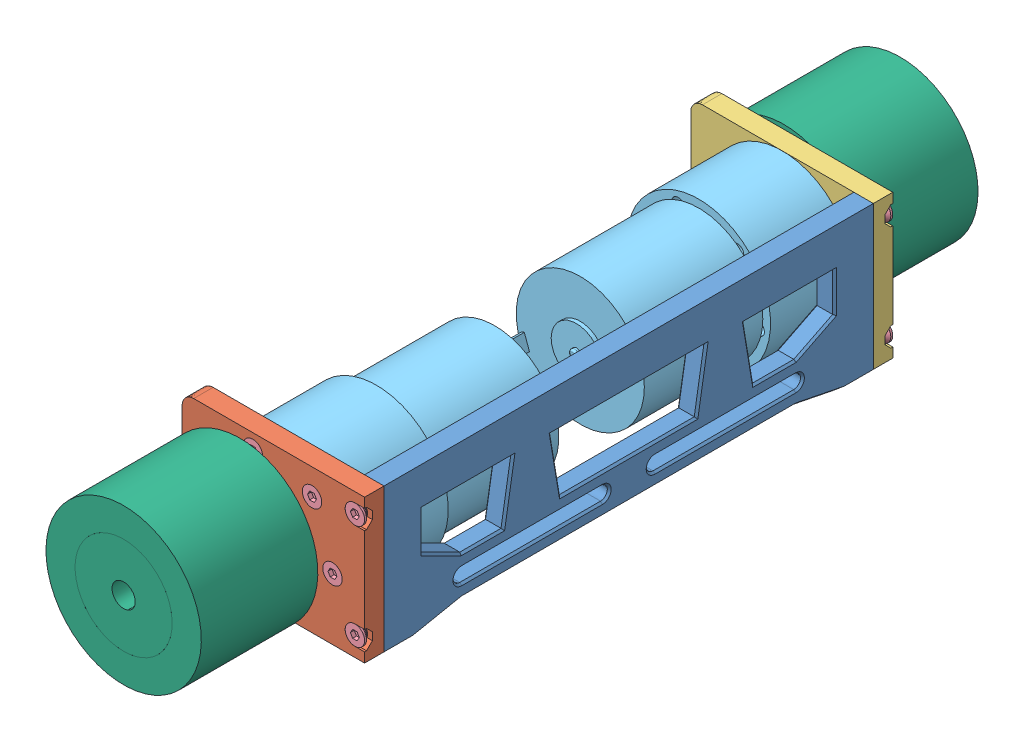
SolidWorks assembly Traccion, configuration Predeterminado. Lengths in mm.
Overall size (55.68 51.27 200).
25 component instances, 6 part files, 28 mates.
Components (placement in the parent):
- Struct_1-1: Struct_1 [Predeterminado] at (-7.0782 16.7308 63) size (5 37 126)
- Bracket_motorD-1: Bracket_motorD [Predeterminado] at (-28.0782 3.2308 189) size (47 37 5)
- Bracket_motorI-1: Bracket_motorI [Predeterminado] at (-28.0782 3.2308 58) size (47 37 5)
- Tornillo M3x15-1: Tornillo M3x15 [Predeterminado] at (-7.0828 -10.2692 179) size (5 5 15.24)
- Tornillo M3x15-2: Tornillo M3x15 [Predeterminado] at (-7.0828 16.7308 179) size (5 5 15.24)
- Tornillo M3x15-3: Tornillo M3x15 [Predeterminado] at (-7.0828 -10.2692 73) x (1 0 0) z (0 0 -1) size (5 5 15.24)
- Tornillo M3x15-4: Tornillo M3x15 [Predeterminado] at (-7.0828 16.7308 73) x (1 0 0) z (0 0 -1) size (5 5 15.24)
- Tornillo M3x15-5: Tornillo M3x15 [Predeterminado] at (-18.1216 15.0668 179) size (5 5 15.24)
- Tornillo M3x15-6: Tornillo M3x15 [Predeterminado] at (-38.0347 -8.6051 179) size (5 5 15.24)
- Tornillo M3x15-7: Tornillo M3x15 [Predeterminado] at (-33.3501 17.7714 179) size (5 5 15.24)
- Tornillo M3x15-8: Tornillo M3x15 [Predeterminado] at (-22.8062 -11.3098 179) size (5 5 15.24)
- Tornillo M3x15-9: Tornillo M3x15 [Predeterminado] at (-43.3067 5.9355 179) size (5 5 15.24)
- Tornillo M3x15-10: Tornillo M3x15 [Predeterminado] at (-12.8497 0.5262 179) size (5 5 15.24)
- Tornillo M3x15-11: Tornillo M3x15 [Predeterminado] at (-22.8062 -11.3098 73) x (-1 0 0) z (0 0 -1) size (5 5 15.24)
- Tornillo M3x15-12: Tornillo M3x15 [Predeterminado] at (-18.1216 15.0668 73) x (-1 0 0) z (0 0 -1) size (5 5 15.24)
- Tornillo M3x15-13: Tornillo M3x15 [Predeterminado] at (-12.8497 0.5262 73) x (-1 0 0) z (0 0 -1) size (5 5 15.24)
- Tornillo M3x15-14: Tornillo M3x15 [Predeterminado] at (-33.3501 17.7714 73) x (-1 0 0) z (0 0 -1) size (5 5 15.24)
- Tornillo M3x15-15: Tornillo M3x15 [Predeterminado] at (-43.3067 5.9355 73) x (-1 0 0) z (0 0 -1) size (5 5 15.24)
- Tornillo M3x15-16: Tornillo M3x15 [Predeterminado] at (-38.0347 -8.6051 73) x (-1 0 0) z (0 0 -1) size (5 5 15.24)
- Motor+Rueda-1: Motor+Rueda [Predeterminado] at (-36.1449 1.5801 91.875) x (-0.939693 -0.34202 0) z (0 0 1) size (40 40 170.38)
  - Titan-37mm-500rpm-2: Titan-37mm-500rpm [Predeterminado] at (-8.182 1.2078 75.625) x (0 1 0) z (0 0 1) size (37 37 78.75)
  - js4030-wheel-cad-1: js4030-wheel-cad [Predeterminado] at (-21.4262 1.7536 159.125) x (-1 0 0) z (0 0 -1) size (40 40 30)
- Motor+Rueda-2: Motor+Rueda [Predeterminado] at (-35.3187 -0.6899 160.125) x (-0.939693 -0.34202 0) z (0 0 -1) size (40 40 170.38)
  - Titan-37mm-500rpm-2: Titan-37mm-500rpm [Predeterminado] at (-8.182 1.2078 75.625) x (0 1 0) z (0 0 1) size (37 37 78.75)
  - js4030-wheel-cad-1: js4030-wheel-cad [Predeterminado] at (-21.4262 1.7536 159.125) x (-1 0 0) z (0 0 -1) size (40 40 30)
Mates (geometry in assembly coordinates):
- Coincidente1: coincident aligned: line of Struct_1-1 through (-4.5782 -15.2692 189) axis (0 1 0); line of Bracket_motorD-1 through (-4.5782 -15.2692 189) axis (0 1 0)
- Coincidente2: coincident aligned: plane of Struct_1-1 through (-9.5782 21.7308 189) normal (0 1 0); plane of Bracket_motorD-1 through (-46.5782 21.7308 194) normal (0 1 0)
- Coincidente3: coincident aligned: plane of Struct_1-1 through (-4.5782 11.7308 189) normal (1 0 0); plane of Bracket_motorD-1 through (-4.5782 3.2308 189) normal (1 0 0)
- Coincidente4: coincident anti-aligned: line of Struct_1-1 through (-4.5782 -15.2692 63) axis (0 1 0); line of Bracket_motorI-1 through (-4.5782 21.7308 63) axis (0 -1 0)
- Coincidente5: coincident aligned: plane of Struct_1-1 through (-9.5782 21.7308 189) normal (0 1 0); plane of Bracket_motorI-1 through (-46.5782 21.7308 63) normal (0 1 0)
- Coincidente6: coincident aligned: plane of Struct_1-1 through (-4.5782 11.7308 189) normal (1 0 0); plane of Bracket_motorI-1 through (-4.5782 3.2308 58) normal (1 0 0)
- Coincidente7: coincident aligned: cone of Bracket_motorD-1 through (-7.0828 -10.2692 193.5) axis (0 0 -1); cone of Tornillo M3x15-1 through (-7.0828 -10.2692 193.5) axis (0 0 -1)
- Coincidente8: coincident aligned: cone of Bracket_motorD-1 through (-7.0828 16.7308 193.5) axis (0 0 -1); cone of Tornillo M3x15-2 through (-7.0828 16.7308 193.5) axis (0 0 -1)
- Coincidente9: coincident aligned: cone of Bracket_motorI-1 through (-7.0828 -10.2692 58.5) axis (0 0 1); cone of Tornillo M3x15-3 through (-7.0828 -10.2692 58.5) axis (0 0 1)
- Coincidente10: coincident aligned: cone of Bracket_motorI-1 through (-7.0828 16.7308 58.5) axis (0 0 1); cone of Tornillo M3x15-4 through (-7.0828 16.7308 58.5) axis (0 0 1)
- Coincidente11: coincident anti-aligned: plane of Bracket_motorI-1 through (-28.0782 3.2308 63) normal (0 0 1); plane of Motor+Rueda-2/Titan-37mm-500rpm-2 through (-28.0432 3.2435 63) normal (0 0 -1)
- Concéntrica1: concentric anti-aligned: cylinder of Bracket_motorI-1 through (-34.6232 0.8486 58) axis (0 0 1) radius 6; cylinder of Motor+Rueda-2/Titan-37mm-500rpm-2 through (-34.6232 0.8486 63) axis (0 0 -1) radius 6
- Coincidente12: coincident anti-aligned: plane of Bracket_motorD-1 through (-28.0782 3.2308 189) normal (0 0 -1); plane of Motor+Rueda-1/Titan-37mm-500rpm-2 through (-28.0432 3.2435 189) normal (0 0 1)
- Concéntrica2: concentric aligned: cylinder of Bracket_motorD-1 through (-34.6232 0.8486 189) axis (0 0 1) radius 6; cylinder of Motor+Rueda-1/Titan-37mm-500rpm-2 through (-34.6232 0.8486 189) axis (0 0 1) radius 6
- Bloquear1: lock: unknown of Struct_1-1; unknown of Motor+Rueda-1
- Bloquear2: lock: unknown of Struct_1-1; unknown of Motor+Rueda-2
- Coincidente13: coincident aligned: cone of Bracket_motorI-1 through (-22.8062 -11.3098 60) axis (0 0 1); cone of Tornillo M3x15-11 through (-22.8062 -11.3098 58.5) axis (0 0 1)
- Coincidente14: coincident aligned: cone of Bracket_motorI-1 through (-18.1216 15.0668 60) axis (0 0 1); cone of Tornillo M3x15-12 through (-18.1216 15.0668 58.5) axis (0 0 1)
- Coincidente15: coincident aligned: cone of Bracket_motorI-1 through (-12.8497 0.5262 60) axis (0 0 1); cone of Tornillo M3x15-13 through (-12.8497 0.5262 58.5) axis (0 0 1)
- Coincidente16: coincident aligned: cone of Bracket_motorI-1 through (-33.3501 17.7714 60) axis (0 0 1); cone of Tornillo M3x15-14 through (-33.3501 17.7714 58.5) axis (0 0 1)
- Coincidente17: coincident aligned: cone of Bracket_motorI-1 through (-43.3067 5.9355 60) axis (0 0 1); cone of Tornillo M3x15-15 through (-43.3067 5.9355 58.5) axis (0 0 1)
- Coincidente18: coincident aligned: cone of Bracket_motorI-1 through (-38.0347 -8.6051 60) axis (0 0 1); cone of Tornillo M3x15-16 through (-38.0347 -8.6051 58.5) axis (0 0 1)
- Coincidente19: coincident aligned: cone of Bracket_motorD-1 through (-22.8062 -11.3098 192) axis (0 0 -1); cone of Tornillo M3x15-8 through (-22.8062 -11.3098 193.5) axis (0 0 -1)
- Coincidente20: coincident aligned: cone of Bracket_motorD-1 through (-18.1216 15.0668 192) axis (0 0 -1); cone of Tornillo M3x15-5 through (-18.1216 15.0668 193.5) axis (0 0 -1)
- Coincidente21: coincident aligned: cone of Bracket_motorD-1 through (-38.0347 -8.6051 192) axis (0 0 -1); cone of Tornillo M3x15-6 through (-38.0347 -8.6051 193.5) axis (0 0 -1)
- Coincidente22: coincident aligned: cone of Bracket_motorD-1 through (-43.3067 5.9355 192) axis (0 0 -1); cone of Tornillo M3x15-9 through (-43.3067 5.9355 193.5) axis (0 0 -1)
- Coincidente23: coincident aligned: cone of Bracket_motorD-1 through (-33.3501 17.7714 192) axis (0 0 -1); cone of Tornillo M3x15-7 through (-33.3501 17.7714 193.5) axis (0 0 -1)
- Coincidente24: coincident aligned: cone of Bracket_motorD-1 through (-12.8497 0.5262 192) axis (0 0 -1); cone of Tornillo M3x15-10 through (-12.8497 0.5262 193.5) axis (0 0 -1)
